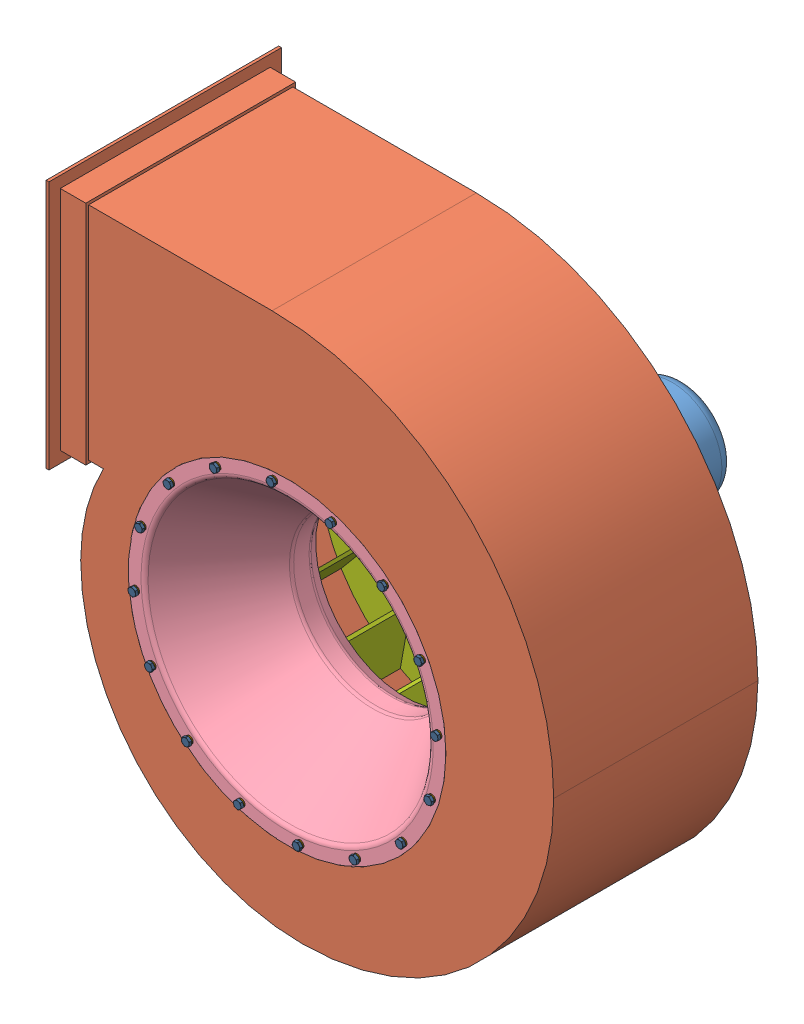
SolidWorks assembly 4-72-5A离心风机, configuration 默认. Lengths in mm.
Overall size (870 965 730).
91 component instances, 12 part files, 42 mates.
Components (placement in the parent):
- Y系列(IP44)三相异步电动机B3_80-132_Y100L1-4-1: Y系列(IP44)三相异步电动机B3_80-132_Y100L1-4 [Y100L1-4] at (28.0379 0 -369.0379) size (279.47 221.71 386)
- 风机外壳（4-72-5A离心风机）-1: 风机外壳（4-72-5A离心风机） [默认] at origin size (870 965 410)
- 连接法兰（4-72-5A离心风机）-1: 连接法兰（4-72-5A离心风机） [默认] at (0 0 172) x (0.99629 0.086056 0) z (0 0 1) size (580 580 6)
- 吸气口（4-72-5A离心风机）-1: 吸气口（4-72-5A离心风机） [默认] at (0 0 175) x (0.953384 -0.301759 0) z (-0.301759 -0.953384 0) size (560 207.5 560)
- 连接法兰（4-72-5A离心风机）-2: 连接法兰（4-72-5A离心风机） [默认] at (0 0 -172) x (0.99629 0.086056 0) z (0 0 1) size (580 580 6)
- 盖板（4-72-5A离心风机）-1: 盖板（4-72-5A离心风机） [默认] at (0 0 -183) x (0.99629 0.086056 0) z (0 0 1) size (560 560 8)
- 连接轴（4-72-5A离心风机）-1: 连接轴（4-72-5A离心风机） [默认] at (0 0 -169) x (1 0 0) z (0 1 0) size (150 60 150)
- 叶片组（4-72-5A离心风机）-1: 叶片组（4-72-5A离心风机） [默认] at (0 0 -85) x (0 0 1) z (0.5 -0.866025 0) size (150 560 560)
- 电机座（4-72-5A离心风机）-1: 电机座（4-72-5A离心风机） [默认] at (0 0 -183) x (0 1 0) z (-1 0 0) size (190 32 200)
- Spring lock washers--Normal type GB-1: Spring lock washers--Normal type GB [GB_FASTENER_WASHER_SW 8] at (-266.5077 -23.0199 -183) size (12.88 12.88 2.1)
- Hex head bolts-Full thread Grade C GB-1: Hex head bolts-Full thread Grade C GB [GB_FASTENER_BOLT_HHBFTC M8X16-C] at (-266.5077 -23.0199 -190.4) x (0 0 1) z (-0.996313 -0.085797 0) size (21.3 15.01 13)
- Spring lock washers--Normal type GB-2: Spring lock washers--Normal type GB [GB_FASTENER_WASHER_SW 8] at (-237.4116 -123.2557 -183) x (0.92388 0.382683 0) z (0 0 1) size (12.88 12.88 2.1)
- Spring lock washers--Normal type GB-3: Spring lock washers--Normal type GB [GB_FASTENER_WASHER_SW 8] at (-172.1719 -204.7269 -183) x (0.707107 0.707107 0) z (0 0 1) size (12.88 12.88 2.1)
- Spring lock washers--Normal type GB-4: Spring lock washers--Normal type GB [GB_FASTENER_WASHER_SW 8] at (-80.7205 -255.0303 -183) x (0.382683 0.92388 0) z (0 0 1) size (12.88 12.88 2.1)
- Spring lock washers--Normal type GB-5: Spring lock washers--Normal type GB [GB_FASTENER_WASHER_SW 8] at (23.0199 -266.5077 -183) x (0 1 0) z (0 0 1) size (12.88 12.88 2.1)
- Spring lock washers--Normal type GB-6: Spring lock washers--Normal type GB [GB_FASTENER_WASHER_SW 8] at (123.2557 -237.4116 -183) x (-0.382683 0.92388 0) z (0 0 1) size (12.88 12.88 2.1)
- Spring lock washers--Normal type GB-7: Spring lock washers--Normal type GB [GB_FASTENER_WASHER_SW 8] at (204.7269 -172.1719 -183) x (-0.707107 0.707107 0) z (0 0 1) size (12.88 12.88 2.1)
- Spring lock washers--Normal type GB-8: Spring lock washers--Normal type GB [GB_FASTENER_WASHER_SW 8] at (255.0303 -80.7205 -183) x (-0.92388 0.382683 0) z (0 0 1) size (12.88 12.88 2.1)
- Spring lock washers--Normal type GB-9: Spring lock washers--Normal type GB [GB_FASTENER_WASHER_SW 8] at (266.5077 23.0199 -183) x (-1 0 0) z (0 0 1) size (12.88 12.88 2.1)
- Spring lock washers--Normal type GB-10: Spring lock washers--Normal type GB [GB_FASTENER_WASHER_SW 8] at (237.4116 123.2557 -183) x (-0.92388 -0.382683 0) z (0 0 1) size (12.88 12.88 2.1)
- Spring lock washers--Normal type GB-11: Spring lock washers--Normal type GB [GB_FASTENER_WASHER_SW 8] at (172.1719 204.7269 -183) x (-0.707107 -0.707107 0) z (0 0 1) size (12.88 12.88 2.1)
- Spring lock washers--Normal type GB-12: Spring lock washers--Normal type GB [GB_FASTENER_WASHER_SW 8] at (80.7205 255.0303 -183) x (-0.382683 -0.92388 0) z (0 0 1) size (12.88 12.88 2.1)
- Spring lock washers--Normal type GB-13: Spring lock washers--Normal type GB [GB_FASTENER_WASHER_SW 8] at (-23.0199 266.5077 -183) x (0 -1 0) z (0 0 1) size (12.88 12.88 2.1)
- Spring lock washers--Normal type GB-14: Spring lock washers--Normal type GB [GB_FASTENER_WASHER_SW 8] at (-123.2557 237.4116 -183) x (0.382683 -0.92388 0) z (0 0 1) size (12.88 12.88 2.1)
- Spring lock washers--Normal type GB-15: Spring lock washers--Normal type GB [GB_FASTENER_WASHER_SW 8] at (-204.7269 172.1719 -183) x (0.707107 -0.707107 0) z (0 0 1) size (12.88 12.88 2.1)
- Spring lock washers--Normal type GB-16: Spring lock washers--Normal type GB [GB_FASTENER_WASHER_SW 8] at (-255.0303 80.7205 -183) x (0.92388 -0.382683 0) z (0 0 1) size (12.88 12.88 2.1)
- Hex head bolts-Full thread Grade C GB-2: Hex head bolts-Full thread Grade C GB [GB_FASTENER_BOLT_HHBFTC M8X16-C] at (-237.4116 -123.2557 -190.4) x (0 0 1) z (-0.88764 -0.460538 0) size (21.3 15.01 13)
- Hex head bolts-Full thread Grade C GB-3: Hex head bolts-Full thread Grade C GB [GB_FASTENER_BOLT_HHBFTC M8X16-C] at (-172.1719 -204.7269 -190.4) x (0 0 1) z (-0.643832 -0.765167 0) size (21.3 15.01 13)
- Hex head bolts-Full thread Grade C GB-4: Hex head bolts-Full thread Grade C GB [GB_FASTENER_BOLT_HHBFTC M8X16-C] at (-80.7205 -255.0303 -190.4) x (0 0 1) z (-0.302006 -0.953306 0) size (21.3 15.01 13)
- Hex head bolts-Full thread Grade C GB-5: Hex head bolts-Full thread Grade C GB [GB_FASTENER_BOLT_HHBFTC M8X16-C] at (23.0199 -266.5077 -190.4) x (0 0 1) z (0.085797 -0.996313 0) size (21.3 15.01 13)
- Hex head bolts-Full thread Grade C GB-6: Hex head bolts-Full thread Grade C GB [GB_FASTENER_BOLT_HHBFTC M8X16-C] at (123.2557 -237.4116 -190.4) x (0 0 1) z (0.460538 -0.88764 0) size (21.3 15.01 13)
- Hex head bolts-Full thread Grade C GB-7: Hex head bolts-Full thread Grade C GB [GB_FASTENER_BOLT_HHBFTC M8X16-C] at (204.7269 -172.1719 -190.4) x (0 0 1) z (0.765167 -0.643832 0) size (21.3 15.01 13)
- Hex head bolts-Full thread Grade C GB-8: Hex head bolts-Full thread Grade C GB [GB_FASTENER_BOLT_HHBFTC M8X16-C] at (255.0303 -80.7205 -190.4) x (0 0 1) z (0.953306 -0.302006 0) size (21.3 15.01 13)
- Hex head bolts-Full thread Grade C GB-9: Hex head bolts-Full thread Grade C GB [GB_FASTENER_BOLT_HHBFTC M8X16-C] at (266.5077 23.0199 -190.4) x (0 0 1) z (0.996313 0.085797 0) size (21.3 15.01 13)
- Hex head bolts-Full thread Grade C GB-10: Hex head bolts-Full thread Grade C GB [GB_FASTENER_BOLT_HHBFTC M8X16-C] at (237.4116 123.2557 -190.4) x (0 0 1) z (0.88764 0.460538 0) size (21.3 15.01 13)
- Hex head bolts-Full thread Grade C GB-11: Hex head bolts-Full thread Grade C GB [GB_FASTENER_BOLT_HHBFTC M8X16-C] at (172.1719 204.7269 -190.4) x (0 0 1) z (0.643832 0.765167 0) size (21.3 15.01 13)
- Hex head bolts-Full thread Grade C GB-12: Hex head bolts-Full thread Grade C GB [GB_FASTENER_BOLT_HHBFTC M8X16-C] at (80.7205 255.0303 -190.4) x (0 0 1) z (0.302006 0.953306 0) size (21.3 15.01 13)
- Hex head bolts-Full thread Grade C GB-13: Hex head bolts-Full thread Grade C GB [GB_FASTENER_BOLT_HHBFTC M8X16-C] at (-23.0199 266.5077 -190.4) x (0 0 1) z (-0.085797 0.996313 0) size (21.3 15.01 13)
- Hex head bolts-Full thread Grade C GB-14: Hex head bolts-Full thread Grade C GB [GB_FASTENER_BOLT_HHBFTC M8X16-C] at (-123.2557 237.4116 -190.4) x (0 0 1) z (-0.460538 0.88764 0) size (21.3 15.01 13)
- Hex head bolts-Full thread Grade C GB-15: Hex head bolts-Full thread Grade C GB [GB_FASTENER_BOLT_HHBFTC M8X16-C] at (-204.7269 172.1719 -190.4) x (0 0 1) z (-0.765167 0.643832 0) size (21.3 15.01 13)
- Hex head bolts-Full thread Grade C GB-16: Hex head bolts-Full thread Grade C GB [GB_FASTENER_BOLT_HHBFTC M8X16-C] at (-255.0303 80.7205 -190.4) x (0 0 1) z (-0.953306 0.302006 0) size (21.3 15.01 13)
- Hex head bolts-Full thread Grade C GB-17: Hex head bolts-Full thread Grade C GB [GB_FASTENER_BOLT_HHBFTC M8X16-C] at (-172.1719 -204.7269 187.4) x (0 0 -1) z (0.604464 0.796632 0) size (21.3 15.01 13)
- Spring lock washers--Normal type GB-17: Spring lock washers--Normal type GB [GB_FASTENER_WASHER_SW 8] at (-172.1719 -204.7269 182.1) x (0.92388 0.382683 0) z (0 0 1) size (12.88 12.88 2.1)
- Hex head bolts-Full thread Grade C GB-18: Hex head bolts-Full thread Grade C GB [GB_FASTENER_BOLT_HHBFTC M8X16-C] at (-80.7205 -255.0303 187.4) x (0 0 -1) z (0.253594 0.967311 0) size (21.3 15.01 13)
- Hex head bolts-Full thread Grade C GB-19: Hex head bolts-Full thread Grade C GB [GB_FASTENER_BOLT_HHBFTC M8X16-C] at (23.0199 -266.5077 187.4) x (0 0 -1) z (-0.135884 0.990725 0) size (21.3 15.01 13)
- Hex head bolts-Full thread Grade C GB-20: Hex head bolts-Full thread Grade C GB [GB_FASTENER_BOLT_HHBFTC M8X16-C] at (123.2557 -237.4116 187.4) x (0 0 -1) z (-0.504674 0.86331 0) size (21.3 15.01 13)
- Hex head bolts-Full thread Grade C GB-21: Hex head bolts-Full thread Grade C GB [GB_FASTENER_BOLT_HHBFTC M8X16-C] at (204.7269 -172.1719 187.4) x (0 0 -1) z (-0.796632 0.604464 0) size (21.3 15.01 13)
- Hex head bolts-Full thread Grade C GB-22: Hex head bolts-Full thread Grade C GB [GB_FASTENER_BOLT_HHBFTC M8X16-C] at (255.0303 -80.7205 187.4) x (0 0 -1) z (-0.967311 0.253594 0) size (21.3 15.01 13)
- Hex head bolts-Full thread Grade C GB-23: Hex head bolts-Full thread Grade C GB [GB_FASTENER_BOLT_HHBFTC M8X16-C] at (266.5077 23.0199 187.4) x (0 0 -1) z (-0.990725 -0.135884 0) size (21.3 15.01 13)
- Hex head bolts-Full thread Grade C GB-24: Hex head bolts-Full thread Grade C GB [GB_FASTENER_BOLT_HHBFTC M8X16-C] at (237.4116 123.2557 187.4) x (0 0 -1) z (-0.86331 -0.504674 0) size (21.3 15.01 13)
- Hex head bolts-Full thread Grade C GB-25: Hex head bolts-Full thread Grade C GB [GB_FASTENER_BOLT_HHBFTC M8X16-C] at (172.1719 204.7269 187.4) x (0 0 -1) z (-0.604464 -0.796632 0) size (21.3 15.01 13)
- Hex head bolts-Full thread Grade C GB-26: Hex head bolts-Full thread Grade C GB [GB_FASTENER_BOLT_HHBFTC M8X16-C] at (80.7205 255.0303 187.4) x (0 0 -1) z (-0.253594 -0.967311 0) size (21.3 15.01 13)
- Hex head bolts-Full thread Grade C GB-27: Hex head bolts-Full thread Grade C GB [GB_FASTENER_BOLT_HHBFTC M8X16-C] at (-23.0199 266.5077 187.4) x (0 0 -1) z (0.135884 -0.990725 0) size (21.3 15.01 13)
- Hex head bolts-Full thread Grade C GB-28: Hex head bolts-Full thread Grade C GB [GB_FASTENER_BOLT_HHBFTC M8X16-C] at (-123.2557 237.4116 187.4) x (0 0 -1) z (0.504674 -0.86331 0) size (21.3 15.01 13)
- Hex head bolts-Full thread Grade C GB-29: Hex head bolts-Full thread Grade C GB [GB_FASTENER_BOLT_HHBFTC M8X16-C] at (-204.7269 172.1719 187.4) x (0 0 -1) z (0.796632 -0.604464 0) size (21.3 15.01 13)
- Hex head bolts-Full thread Grade C GB-30: Hex head bolts-Full thread Grade C GB [GB_FASTENER_BOLT_HHBFTC M8X16-C] at (-255.0303 80.7205 187.4) x (0 0 -1) z (0.967311 -0.253594 0) size (21.3 15.01 13)
- Hex head bolts-Full thread Grade C GB-31: Hex head bolts-Full thread Grade C GB [GB_FASTENER_BOLT_HHBFTC M8X16-C] at (-266.5077 -23.0199 187.4) x (0 0 -1) z (0.990725 0.135884 0) size (21.3 15.01 13)
- Hex head bolts-Full thread Grade C GB-32: Hex head bolts-Full thread Grade C GB [GB_FASTENER_BOLT_HHBFTC M8X16-C] at (-237.4116 -123.2557 187.4) x (0 0 -1) z (0.86331 0.504674 0) size (21.3 15.01 13)
- Spring lock washers--Normal type GB-18: Spring lock washers--Normal type GB [GB_FASTENER_WASHER_SW 8] at (-80.7205 -255.0303 182.1) x (0.707107 0.707107 0) z (0 0 1) size (12.88 12.88 2.1)
- Spring lock washers--Normal type GB-19: Spring lock washers--Normal type GB [GB_FASTENER_WASHER_SW 8] at (23.0199 -266.5077 182.1) x (0.382683 0.92388 0) z (0 0 1) size (12.88 12.88 2.1)
- Spring lock washers--Normal type GB-20: Spring lock washers--Normal type GB [GB_FASTENER_WASHER_SW 8] at (123.2557 -237.4116 182.1) x (0 1 0) z (0 0 1) size (12.88 12.88 2.1)
- Spring lock washers--Normal type GB-21: Spring lock washers--Normal type GB [GB_FASTENER_WASHER_SW 8] at (204.7269 -172.1719 182.1) x (-0.382683 0.92388 0) z (0 0 1) size (12.88 12.88 2.1)
- Spring lock washers--Normal type GB-22: Spring lock washers--Normal type GB [GB_FASTENER_WASHER_SW 8] at (255.0303 -80.7205 182.1) x (-0.707107 0.707107 0) z (0 0 1) size (12.88 12.88 2.1)
- Spring lock washers--Normal type GB-23: Spring lock washers--Normal type GB [GB_FASTENER_WASHER_SW 8] at (266.5077 23.0199 182.1) x (-0.92388 0.382683 0) z (0 0 1) size (12.88 12.88 2.1)
- Spring lock washers--Normal type GB-24: Spring lock washers--Normal type GB [GB_FASTENER_WASHER_SW 8] at (237.4116 123.2557 182.1) x (-1 0 0) z (0 0 1) size (12.88 12.88 2.1)
- Spring lock washers--Normal type GB-25: Spring lock washers--Normal type GB [GB_FASTENER_WASHER_SW 8] at (172.1719 204.7269 182.1) x (-0.92388 -0.382683 0) z (0 0 1) size (12.88 12.88 2.1)
- Spring lock washers--Normal type GB-26: Spring lock washers--Normal type GB [GB_FASTENER_WASHER_SW 8] at (80.7205 255.0303 182.1) x (-0.707107 -0.707107 0) z (0 0 1) size (12.88 12.88 2.1)
- Spring lock washers--Normal type GB-27: Spring lock washers--Normal type GB [GB_FASTENER_WASHER_SW 8] at (-23.0199 266.5077 182.1) x (-0.382683 -0.92388 0) z (0 0 1) size (12.88 12.88 2.1)
- Spring lock washers--Normal type GB-28: Spring lock washers--Normal type GB [GB_FASTENER_WASHER_SW 8] at (-123.2557 237.4116 182.1) x (0 -1 0) z (0 0 1) size (12.88 12.88 2.1)
- Spring lock washers--Normal type GB-29: Spring lock washers--Normal type GB [GB_FASTENER_WASHER_SW 8] at (-204.7269 172.1719 182.1) x (0.382683 -0.92388 0) z (0 0 1) size (12.88 12.88 2.1)
- Spring lock washers--Normal type GB-30: Spring lock washers--Normal type GB [GB_FASTENER_WASHER_SW 8] at (-255.0303 80.7205 182.1) x (0.707107 -0.707107 0) z (0 0 1) size (12.88 12.88 2.1)
- Spring lock washers--Normal type GB-31: Spring lock washers--Normal type GB [GB_FASTENER_WASHER_SW 8] at (-266.5077 -23.0199 182.1) x (0.92388 -0.382683 0) z (0 0 1) size (12.88 12.88 2.1)
- Spring lock washers--Normal type GB-32: Spring lock washers--Normal type GB [GB_FASTENER_WASHER_SW 8] at (-237.4116 -123.2557 182.1) size (12.88 12.88 2.1)
- Hex head bolts-Full thread Grade C GB-33: Hex head bolts-Full thread Grade C GB [GB_FASTENER_BOLT_HHBFTC M10X20-C] at (0 60 -140.6) x (0 0 -1) z (1 0 0) size (26.4 18.48 16)
- Plain washers-N series-Grade A GB-1: Plain washers-N series-Grade A GB [GB_FASTENER_WASHER_PWNA 10] at (0 60 -149) x (-1 0 0) z (0 0 -1) size (20 20 2)
- Hex nuts, style 1-Grades AB GB-1: Hex nuts, style 1-Grades AB GB [GB_FASTENER_NUT_SNAB1 M10-C] at (0 60 -160) size (18.48 16 8.4)
- Hex nuts, style 1-Grades AB GB-2: Hex nuts, style 1-Grades AB GB [GB_FASTENER_NUT_SNAB1 M10-C] at (51.9615 30 -160) x (0.5 -0.866025 0) z (0 0 1) size (18.48 16 8.4)
- Hex nuts, style 1-Grades AB GB-3: Hex nuts, style 1-Grades AB GB [GB_FASTENER_NUT_SNAB1 M10-C] at (51.9615 -30 -160) x (-0.5 -0.866025 0) z (0 0 1) size (18.48 16 8.4)
- Hex nuts, style 1-Grades AB GB-4: Hex nuts, style 1-Grades AB GB [GB_FASTENER_NUT_SNAB1 M10-C] at (0 -60 -160) x (-1 0 0) z (0 0 1) size (18.48 16 8.4)
- Hex nuts, style 1-Grades AB GB-5: Hex nuts, style 1-Grades AB GB [GB_FASTENER_NUT_SNAB1 M10-C] at (-51.9615 -30 -160) x (-0.5 0.866025 0) z (0 0 1) size (18.48 16 8.4)
- Hex nuts, style 1-Grades AB GB-6: Hex nuts, style 1-Grades AB GB [GB_FASTENER_NUT_SNAB1 M10-C] at (-51.9615 30 -160) x (0.5 0.866025 0) z (0 0 1) size (18.48 16 8.4)
- Plain washers-N series-Grade A GB-2: Plain washers-N series-Grade A GB [GB_FASTENER_WASHER_PWNA 10] at (51.9615 30 -149) x (-0.5 0.866025 0) z (0 0 -1) size (20 20 2)
- Plain washers-N series-Grade A GB-3: Plain washers-N series-Grade A GB [GB_FASTENER_WASHER_PWNA 10] at (51.9615 -30 -149) x (0.5 0.866025 0) z (0 0 -1) size (20 20 2)
- Plain washers-N series-Grade A GB-4: Plain washers-N series-Grade A GB [GB_FASTENER_WASHER_PWNA 10] at (0 -60 -149) x (1 0 0) z (0 0 -1) size (20 20 2)
- Plain washers-N series-Grade A GB-5: Plain washers-N series-Grade A GB [GB_FASTENER_WASHER_PWNA 10] at (-51.9615 -30 -149) x (0.5 -0.866025 0) z (0 0 -1) size (20 20 2)
- Plain washers-N series-Grade A GB-6: Plain washers-N series-Grade A GB [GB_FASTENER_WASHER_PWNA 10] at (-51.9615 30 -149) x (-0.5 -0.866025 0) z (0 0 -1) size (20 20 2)
- Hex head bolts-Full thread Grade C GB-34: Hex head bolts-Full thread Grade C GB [GB_FASTENER_BOLT_HHBFTC M10X20-C] at (51.9615 30 -140.6) x (0 0 -1) z (0.5 -0.866025 0) size (26.4 18.48 16)
- Hex head bolts-Full thread Grade C GB-35: Hex head bolts-Full thread Grade C GB [GB_FASTENER_BOLT_HHBFTC M10X20-C] at (51.9615 -30 -140.6) x (0 0 -1) z (-0.5 -0.866025 0) size (26.4 18.48 16)
- Hex head bolts-Full thread Grade C GB-36: Hex head bolts-Full thread Grade C GB [GB_FASTENER_BOLT_HHBFTC M10X20-C] at (0 -60 -140.6) x (0 0 -1) z (-1 0 0) size (26.4 18.48 16)
- Hex head bolts-Full thread Grade C GB-37: Hex head bolts-Full thread Grade C GB [GB_FASTENER_BOLT_HHBFTC M10X20-C] at (-51.9615 -30 -140.6) x (0 0 -1) z (-0.5 0.866025 0) size (26.4 18.48 16)
- Hex head bolts-Full thread Grade C GB-38: Hex head bolts-Full thread Grade C GB [GB_FASTENER_BOLT_HHBFTC M10X20-C] at (-51.9615 30 -140.6) x (0 0 -1) z (0.5 0.866025 0) size (26.4 18.48 16)
Mates (geometry in assembly coordinates):
- 重合1: coincident anti-aligned: plane of 风机外壳（4-72-5A离心风机）-1 through (26.5036 26.5036 175) normal (0 0 -1); plane of 连接法兰（4-72-5A离心风机）-1 through (0 0 175) normal (0 0 1)
- 同心1: concentric anti-aligned: cylinder of 风机外壳（4-72-5A离心风机）-1 through (0 0 -180) axis (0 0 1) radius 280; cylinder of 连接法兰（4-72-5A离心风机）-1 through (0 0 175) axis (0 0 -1) radius 255
- 同心2: concentric aligned: cylinder of 吸气口（4-72-5A离心风机）-1 through (0 0 175) axis (0 0 1) radius 280; cylinder of 风机外壳（4-72-5A离心风机）-1 through (0 0 -180) axis (0 0 1) radius 280
- 重合2: coincident anti-aligned: plane of 连接法兰（4-72-5A离心风机）-1 through (0 0 175) normal (0 0 1); plane of 吸气口（4-72-5A离心风机）-1 through (-266.9476 84.4924 175) normal (0 0 -1)
- 重合3: coincident anti-aligned: plane of 风机外壳（4-72-5A离心风机）-1 through (26.5036 26.5036 -175) normal (0 0 1); plane of 连接法兰（4-72-5A离心风机）-2 through (0 0 -175) normal (0 0 -1)
- 同心3: concentric anti-aligned: cylinder of 风机外壳（4-72-5A离心风机）-1 through (0 0 -180) axis (0 0 1) radius 280; cylinder of 连接法兰（4-72-5A离心风机）-2 through (0 0 -169) axis (0 0 -1) radius 255
- 重合4: coincident aligned: plane of 风机外壳（4-72-5A离心风机）-1 through (0 0 0) normal (0 0 1); plane of assembly
- 重合5: coincident aligned: plane of 风机外壳（4-72-5A离心风机）-1 through (0 0 0) normal (0 1 0); plane of assembly
- 重合6: coincident aligned: plane of 风机外壳（4-72-5A离心风机）-1 through (0 0 0) normal (1 0 0); plane of assembly
- 重合8: coincident aligned: plane of 连接法兰（4-72-5A离心风机）-1; plane of 连接法兰（4-72-5A离心风机）-2
- 重合9: coincident aligned: plane of 连接法兰（4-72-5A离心风机）-2; plane of 盖板（4-72-5A离心风机）-1
- 同心4: concentric anti-aligned: cylinder of 风机外壳（4-72-5A离心风机）-1 through (0 0 -180) axis (0 0 1) radius 280; cylinder of 盖板（4-72-5A离心风机）-1 through (0 0 -175) axis (0 0 -1) radius 280
- 重合10: coincident anti-aligned: plane of 连接法兰（4-72-5A离心风机）-2 through (0 0 -175) normal (0 0 -1); plane of 盖板（4-72-5A离心风机）-1 through (0 0 -175) normal (0 0 1)
- 同心5: concentric aligned: cylinder of 连接轴（4-72-5A离心风机）-1 through (0 0 -199) axis (0 0 -1) radius 25; cylinder of 叶片组（4-72-5A离心风机）-1 through (0 0 -160) axis (0 0 -1) radius 280
- 同心6: concentric aligned: cylinder of 盖板（4-72-5A离心风机）-1 through (0 0 -175) axis (0 0 -1) radius 30; cylinder of 连接轴（4-72-5A离心风机）-1 through (0 0 -199) axis (0 0 -1) radius 25
- 重合14: coincident anti-aligned: plane of 连接轴（4-72-5A离心风机）-1 through (-75 0 -155) normal (0 0 -1); plane of 叶片组（4-72-5A离心风机）-1 through (-242.4871 -140 -155) normal (0 0 1)
- 同心7: concentric anti-aligned: cylinder of Y系列(IP44)三相异步电动机B3_80-132_Y100L1-4-1 through (0 0 -525) axis (0 0 -1) radius 14; cylinder of 连接轴（4-72-5A离心风机）-1 through (0 0 -199) axis (0 0 1) radius 14
- 重合15: coincident aligned: plane of Y系列(IP44)三相异步电动机B3_80-132_Y100L1-4-1 through (-4 -39.6488 -184) normal (1 0 0); plane of 连接轴（4-72-5A离心风机）-1 through (-4 13.4164 -199) normal (1 0 0)
- 重合16: coincident anti-aligned: plane of 盖板（4-72-5A离心风机）-1 through (0 0 -175) normal (0 0 1); plane of 连接轴（4-72-5A离心风机）-1 through (-40 0 -175) normal (0 0 -1)
- 重合17: coincident aligned: plane of Y系列(IP44)三相异步电动机B3_80-132_Y100L1-4-1 through (0 0 -139) normal (0 0 1); plane of 连接轴（4-72-5A离心风机）-1 through (0 0 -139) normal (0 0 1)
- 同心8: concentric aligned: cylinder of 电机座（4-72-5A离心风机）-1 through (0 0 -183) axis (0 0 -1) radius 56; cylinder of Y系列(IP44)三相异步电动机B3_80-132_Y100L1-4-1 through (0 0 -525) axis (0 0 -1) radius 56
- 重合18: coincident anti-aligned: plane of 盖板（4-72-5A离心风机）-1 through (0 0 -183) normal (0 0 -1); plane of 电机座（4-72-5A离心风机）-1 through (0 0 -183) normal (0 0 1)
- 平行1: parallel aligned: plane of 电机座（4-72-5A离心风机）-1 through (86.2002 -90 -183) normal (0 -1 0); plane of Y系列(IP44)三相异步电动机B3_80-132_Y100L1-4-1 through (-60.5 -100 -420) normal (0 -1 0)
- 平行2: parallel anti-aligned: plane of 电机座（4-72-5A离心风机）-1; plane of 风机外壳（4-72-5A离心风机）-1 through (-380 138.0073 180) normal (0 1 0)
- 同心9: concentric anti-aligned: cylinder of 连接法兰（4-72-5A离心风机）-1 through (80.7205 255.0303 169) axis (0 0 -1) radius 3.4; cylinder of 吸气口（4-72-5A离心风机）-1 through (80.7205 255.0303 180) axis (0 0 1) radius 4.5
- 重合19: coincident anti-aligned: plane of 盖板（4-72-5A离心风机）-1 through (0 0 -183) normal (0 0 -1); plane of Spring lock washers--Normal type GB-1 through (-266.5077 -23.0199 -183) normal (0 0 1)
- 同心11: concentric aligned: cylinder of Spring lock washers--Normal type GB-1 through (-266.5077 -23.0199 -185.1) axis (0 0 1) radius 4.34; cylinder of 盖板（4-72-5A离心风机）-1 through (-266.5077 -23.0199 -175) axis (0 0 1) radius 4.5
- 重合20: coincident anti-aligned: plane of Spring lock washers--Normal type GB-1 through (-266.5077 -23.0199 -185.1) normal (0 0 -1); plane of Hex head bolts-Full thread Grade C GB-1 through (-279.4597 -24.1353 -185.1) normal (0 0 1)
- 同心12: concentric anti-aligned: cylinder of Spring lock washers--Normal type GB-1 through (-266.5077 -23.0199 -185.1) axis (0 0 1) radius 4.34; cylinder of Hex head bolts-Full thread Grade C GB-1 through (-266.5077 -23.0199 -169.1) axis (0 0 -1) radius 4
- 同心13: concentric aligned: cylinder of Hex head bolts-Full thread Grade C GB-17 through (-172.1719 -204.7269 166.1) axis (0 0 1) radius 4; cylinder of Spring lock washers--Normal type GB-17 through (-172.1719 -204.7269 180) axis (0 0 1) radius 4.34
- 同心14: concentric aligned: cylinder of 吸气口（4-72-5A离心风机）-1 through (-172.1719 -204.7269 180) axis (0 0 1) radius 4.5; cylinder of Hex head bolts-Full thread Grade C GB-17 through (-172.1719 -204.7269 166.1) axis (0 0 1) radius 4
- 重合21: coincident anti-aligned: plane of 吸气口（4-72-5A离心风机）-1 through (-266.9476 84.4924 180) normal (0 0 1); plane of Spring lock washers--Normal type GB-17 through (-172.1719 -204.7269 180) normal (0 0 -1)
- 重合22: coincident anti-aligned: plane of Hex head bolts-Full thread Grade C GB-17 through (-164.3138 -194.3707 182.1) normal (0 0 -1); plane of Spring lock washers--Normal type GB-17 through (-172.1719 -204.7269 182.1) normal (0 0 1)
- 同心15: concentric anti-aligned: cylinder of 连接轴（4-72-5A离心风机）-1 through (51.9615 30 -155) axis (0 0 -1) radius 5.5; cylinder of 叶片组（4-72-5A离心风机）-1 through (51.9615 30 -155) axis (0 0 1) radius 5.5
- 同心16: concentric anti-aligned: cylinder of Hex head bolts-Full thread Grade C GB-33 through (0 60 -167) axis (0 0 1) radius 5; cylinder of Plain washers-N series-Grade A GB-1 through (0 60 -147) axis (0 0 -1) radius 5.25
- 重合23: coincident anti-aligned: plane of Hex head bolts-Full thread Grade C GB-33 through (16 60 -147) normal (0 0 -1); plane of Plain washers-N series-Grade A GB-1 through (0 60 -147) normal (0 0 1)
- 重合24: coincident anti-aligned: plane of 连接轴（4-72-5A离心风机）-1 through (-25 0 -149) normal (0 0 1); plane of Plain washers-N series-Grade A GB-1 through (0 60 -149) normal (0 0 -1)
- 同心17: concentric anti-aligned: cylinder of 连接轴（4-72-5A离心风机）-1 through (0 60 -155) axis (0 0 -1) radius 5.5; cylinder of Hex head bolts-Full thread Grade C GB-33 through (0 60 -167) axis (0 0 1) radius 5
- 同心18: concentric aligned: cylinder of Hex head bolts-Full thread Grade C GB-33 through (0 60 -167) axis (0 0 1) radius 5; cylinder of Hex nuts, style 1-Grades AB GB-1 through (0 60 -168.4) axis (0 0 1) radius 4.188
- 重合25: coincident anti-aligned: plane of 叶片组（4-72-5A离心风机）-1 through (-242.4871 -140 -160) normal (0 0 -1); plane of Hex nuts, style 1-Grades AB GB-1 through (9.2376 60 -160) normal (0 0 1)
- 局部圆周阵列2: unknown: line of 风机外壳（4-72-5A离心风机）-1 through (0 0 180) axis (0 0 1)
- 局部圆周阵列3: unknown: line of 连接轴（4-72-5A离心风机）-1 through (0 0 -149) axis (0 0 -1)
